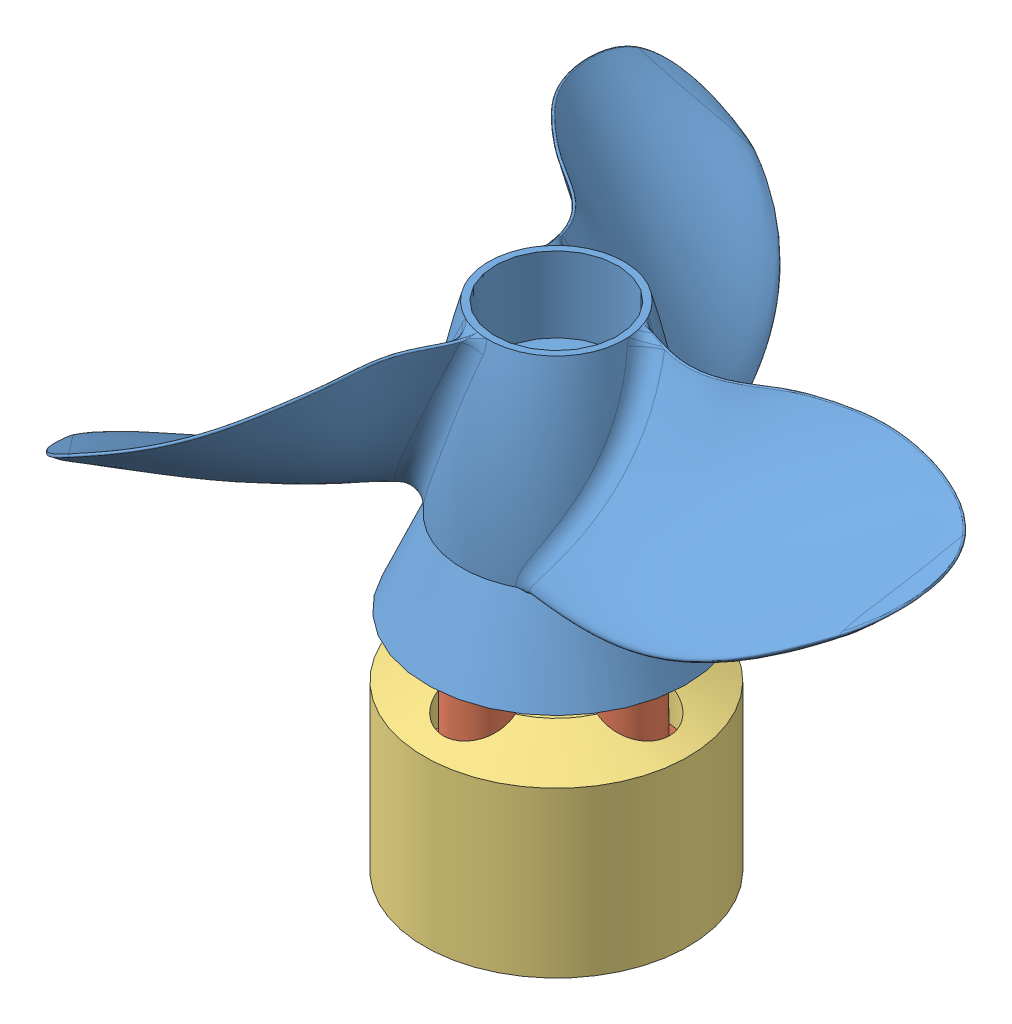
SolidWorks assembly Ensamblaje1, configuration Predeterminado. Lengths in mm.
Overall size (97.87 52.51 97.77).
4 component instances, 4 part files, 7 mates.
Components (placement in the parent):
- turbina-1: turbina [Predeterminado] at (0 16.3978 0) x (0 1 0) z (0.733458 0 -0.679735) size (28.51 68.31 70.13)
- SoporteHelice-1: SoporteHelice [Predeterminado] at (0 -2 0) x (-0.036401 0 0.999337) z (-0.999337 0 -0.036401) size (22.13 12.01 22.13)
- Carcasa-1: Carcasa [Predeterminado] at origin size (28 32.5 28)
- Tornillo-1: Tornillo [Predeterminado] at (0 15.1 0) size (12 24.5 12)
Mates (geometry in assembly coordinates):
- Coincidente2: coordinate: point of Carcasa-1
- Concéntrica2: concentric anti-aligned: cylinder of SoporteHelice-1 through (0 -4.8 0) axis (0 1 0) radius 4.65; cylinder of Carcasa-1 through (0 -19.447 0) axis (0 -1 0) radius 1.5
- Coincidente3: coincident anti-aligned: plane of SoporteHelice-1 through (0 0 0) normal (0 1 0); plane of Carcasa-1 through (0 0 0) normal (0 -1 0)
- Concéntrica3: concentric aligned: cylinder of Carcasa-1 through (0 -19.447 0) axis (0 -1 0) radius 1.5; cylinder of Tornillo-1 through (0 -3.019 0) axis (0 -1 0) radius 1.5
- Coincidente4: coincident anti-aligned: plane of Carcasa-1 through (0 5.5 0) normal (0 1 0); plane of Tornillo-1 through (-5.8 5.5 0) normal (0 -1 0)
- Concéntrica4: concentric aligned: cylinder of turbina-1 through (0 16.3978 0) axis (0 -1 0) radius 2.5; cylinder of Tornillo-1 through (0 -3.019 0) axis (0 -1 0) radius 2.375
- Coincidente6: coincident anti-aligned: plane of turbina-1 through (8.244 12 0.3134) normal (0 -1 0); plane of SoporteHelice-1 through (8.3445 12 0.3039) normal (0 1 0)
